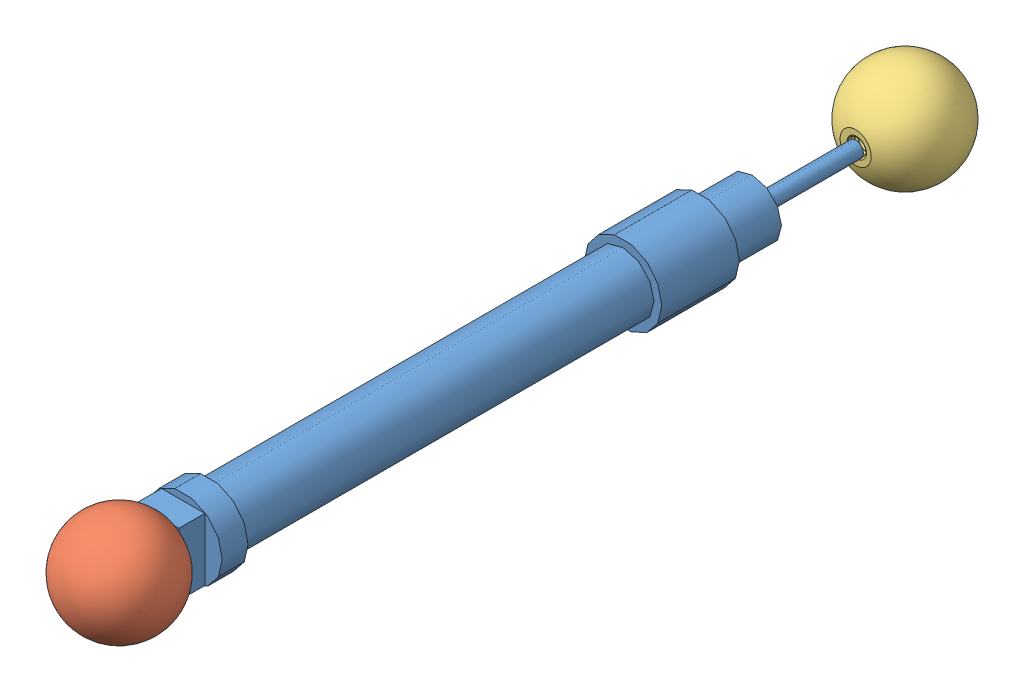
SolidWorks assembly actuador esferas, configuration Predeterminado. Lengths in mm.
Overall size (20.29 20.29 171.92).
3 component instances, 3 part files, 2 mates.
Components (placement in the parent):
- Actuador-1: Actuador [Predeterminado] at (4.3361 -1.3734 111.045) size (15.01 15.01 143.39)
- esfera rosca grande-1: esfera rosca grande [Predeterminado] at (-7.3726 3.8234 230.045) x (0.999897 0.01438 0) z (-0.01438 0.999897 0) size (20 17.92 20)
- esfera rosca chica-1: esfera rosca chica [Predeterminado] at (-7.3534 3.8586 67.045) x (1 0 0) z (0 -1 0) size (20 19.88 20)
Mates (geometry in assembly coordinates):
- Coincidente1: coincident anti-aligned: plane of Actuador-1 through (4.3361 -1.3734 216.045) normal (0 0 1); plane of esfera rosca grande-1 through (-7.3726 3.8234 216.045) normal (0 0 -1)
- Coincidente2: coincident anti-aligned: plane of Actuador-1 through (-7.3341 3.617 81.045) normal (0 0 -1); plane of esfera rosca chica-1 through (-7.3534 3.8586 81.045) normal (0 0 1)
